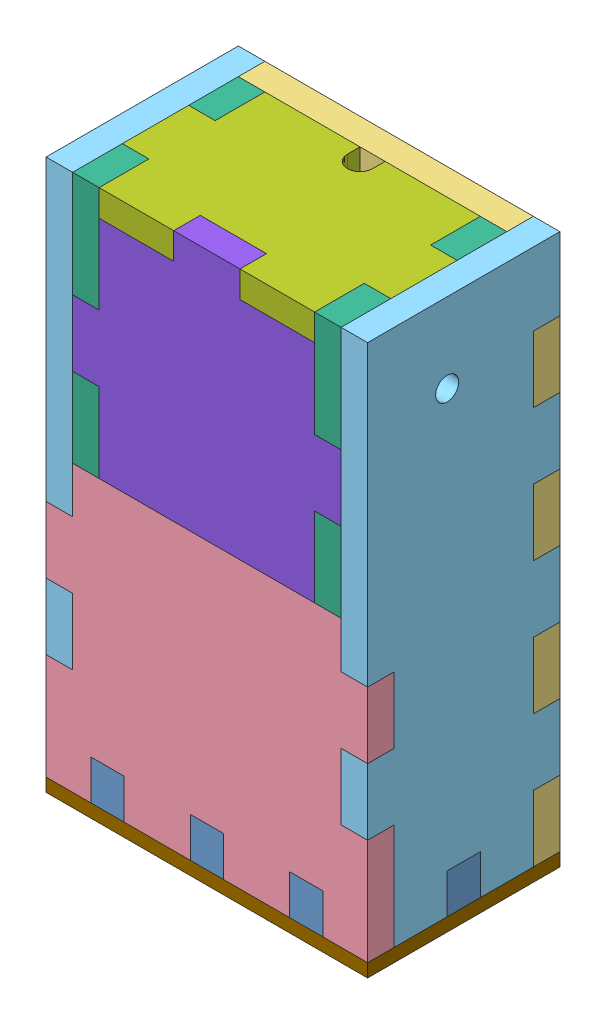
SolidWorks assembly Anduri_karp, configuration Default. Lengths in mm.
Overall size (48.5 83 29).
11 component instances, 9 part files, 30 mates.
Components (placement in the parent):
- andur_esi-1: andur_esi [Default] at (-297.9854 64.2647 100.047) size (48.5 6 29)
- andur_tof-1: andur_tof [Default] at (-282.4854 67.5647 111.047) x (-1 0 0) z (0 0 -1) size (40.2 64.6 13.79)
- andur_alumine-1: andur_alumine [Default] at (-269.9854 146.8647 91.047) x (0 -1 0) z (-1 0 0) size (81 4 48.5)
- andur_pealmine-1: andur_pealmine [Default] at (-310.4854 108.8647 120.047) x (0 -1 0) z (1 0 0) size (43 4 48.5)
- andur_külg-1: andur_külg [Default] at (-269.9854 146.8647 95.047) x (0 -1 0) z (0 0 1) size (81 4 29)
- andur_külg-2: andur_külg [Default] at (-314.4854 146.8647 95.047) x (0 -1 0) z (0 0 1) size (81 4 29)
- andur_kaane_külg-1: andur_kaane_külg [Default] at (-310.4854 146.8647 95.047) x (0 -1 0) z (0 0 1) size (38 4 25)
- andur_kaane_külg-2: andur_kaane_külg [Default] at (-273.9854 146.8647 95.047) x (0 -1 0) z (0 0 1) size (38 4 25)
- andur_kaane_juhtmeauk-1: andur_kaane_juhtmeauk [Default] at (-306.4854 142.8647 95.047) size (40.5 4 25)
- andur_kaane_lagi-1: andur_kaane_lagi [Default] at (-306.4854 108.8647 120.047) x (1 0 0) z (0 1 0) size (40.5 4 38)
- pleksiklaas_2-1: pleksiklaas_2 [Default] at (-314.4854 63.8647 91.047) size (48.5 2 29)
Mates (geometry in assembly coordinates):
- Coincident2: coincident anti-aligned: plane of andur_esi-1 through (-282.4854 71.8647 100.047) normal (0 0 1); plane of andur_tof-1 through (-282.4854 69.1647 100.047) normal (0 0 -1)
- Coincident3: coincident anti-aligned: plane of andur_esi-1 through (-297.9854 71.8647 100.047) normal (0 1 0); plane of andur_tof-1 through (-282.4854 71.8647 111.047) normal (0 -1 0)
- Coincident4: coincident anti-aligned: plane of andur_esi-1 through (-282.4854 71.8647 102.647) normal (-1 0 0); plane of andur_tof-1 through (-282.4854 69.1647 111.047) normal (1 0 0)
- Coincident5: coincident anti-aligned: plane of andur_esi-1 through (-297.9854 71.8647 100.047) normal (0 1 0); plane of andur_alumine-1 through (-269.9854 71.8647 95.047) normal (0 -1 0)
- Coincident6: coincident anti-aligned: plane of andur_esi-1 through (-310.4854 71.8647 95.047) normal (0 0 -1); plane of andur_alumine-1 through (-269.9854 146.8647 95.047) normal (0 0 1)
- Coincident7: coincident aligned: plane of andur_esi-1 through (-269.9854 71.8647 95.047) normal (1 0 0); plane of andur_alumine-1 through (-269.9854 146.8647 95.047) normal (1 0 0)
- Coincident8: coincident aligned: plane of andur_esi-1 through (-307.7354 65.8647 120.047) normal (0 0 1); plane of andur_pealmine-1 through (-310.4854 108.8647 120.047) normal (0 0 1)
- Coincident9: coincident aligned: plane of andur_alumine-1 through (-269.9854 146.8647 95.047) normal (1 0 0); plane of andur_pealmine-1 through (-269.9854 108.8647 116.047) normal (1 0 0)
- Coincident10: coincident anti-aligned: plane of andur_esi-1 through (-297.9854 71.8647 100.047) normal (0 1 0); plane of andur_pealmine-1 through (-310.4854 71.8647 116.047) normal (0 -1 0)
- Coincident11: coincident anti-aligned: plane of andur_esi-1 through (-269.9854 71.8647 95.047) normal (1 0 0); plane of andur_külg-1 through (-269.9854 146.8647 95.047) normal (-1 0 0)
- Coincident12: coincident anti-aligned: plane of andur_esi-1 through (-297.9854 71.8647 100.047) normal (0 1 0); plane of andur_külg-1 through (-265.9854 71.8647 95.047) normal (0 -1 0)
- Coincident13: coincident anti-aligned: plane of andur_pealmine-1 through (-310.4854 108.8647 116.047) normal (0 0 -1); plane of andur_külg-1 through (-265.9854 146.8647 116.047) normal (0 0 1)
- Coincident14: coincident anti-aligned: plane of andur_esi-1 through (-310.4854 71.8647 95.047) normal (-1 0 0); plane of andur_külg-2 through (-310.4854 146.8647 95.047) normal (1 0 0)
- Coincident15: coincident aligned: plane of andur_esi-1 through (-297.9854 65.8647 100.047) normal (0 -1 0); plane of andur_külg-2 through (-314.4854 65.8647 95.047) normal (0 -1 0)
- Coincident16: coincident aligned: plane of andur_alumine-1 through (-269.9854 146.8647 91.047) normal (0 0 -1); plane of andur_külg-2 through (-314.4854 75.8647 91.047) normal (0 0 -1)
- Coincident17: coincident anti-aligned: plane of andur_külg-2 through (-310.4854 146.8647 95.047) normal (1 0 0); plane of andur_kaane_külg-1 through (-310.4854 146.8647 95.047) normal (-1 0 0)
- Coincident18: coincident anti-aligned: plane of andur_alumine-1 through (-269.9854 146.8647 95.047) normal (0 0 1); plane of andur_kaane_külg-1 through (-306.4854 146.8647 95.047) normal (0 0 -1)
- Coincident19: coincident aligned: plane of andur_külg-2 through (-310.4854 146.8647 95.047) normal (0 1 0); plane of andur_kaane_külg-1 through (-306.4854 146.8647 95.047) normal (0 1 0)
- Coincident20: coincident aligned: plane of andur_kaane_külg-1 through (-306.4854 146.8647 120.047) normal (0 0 1); plane of andur_kaane_külg-2 through (-269.9854 146.8647 120.047) normal (0 0 1)
- Coincident21: coincident aligned: plane of andur_kaane_külg-1 through (-306.4854 146.8647 95.047) normal (0 1 0); plane of andur_kaane_külg-2 through (-269.9854 146.8647 95.047) normal (0 1 0)
- Coincident22: coincident anti-aligned: plane of andur_külg-1 through (-269.9854 146.8647 95.047) normal (-1 0 0); plane of andur_kaane_külg-2 through (-269.9854 146.8647 95.047) normal (1 0 0)
- Coincident23: coincident aligned: plane of andur_kaane_külg-1 through (-306.4854 146.8647 95.047) normal (0 1 0); plane of andur_kaane_juhtmeauk-1 through (-306.4854 146.8647 95.047) normal (0 1 0)
- Coincident24: coincident aligned: plane of andur_kaane_külg-1 through (-306.4854 146.8647 120.047) normal (0 0 1); plane of andur_kaane_juhtmeauk-1 through (-306.4854 146.8647 120.047) normal (0 0 1)
- Coincident25: coincident anti-aligned: plane of andur_kaane_külg-2 through (-273.9854 146.8647 95.047) normal (-1 0 0); plane of andur_kaane_juhtmeauk-1 through (-273.9854 146.8647 95.047) normal (1 0 0)
- Coincident26: coincident aligned: plane of andur_kaane_külg-1 through (-306.4854 108.8647 95.047) normal (0 -1 0); plane of andur_kaane_lagi-1 through (-306.4854 108.8647 116.047) normal (0 -1 0)
- Coincident27: coincident aligned: plane of andur_kaane_külg-1 through (-306.4854 146.8647 120.047) normal (0 0 1); plane of andur_kaane_lagi-1 through (-306.4854 108.8647 120.047) normal (0 0 1)
- Coincident28: coincident anti-aligned: plane of andur_kaane_külg-1 through (-306.4854 146.8647 95.047) normal (1 0 0); plane of andur_kaane_lagi-1 through (-306.4854 108.8647 116.047) normal (-1 0 0)
- Coincident29: coincident: plane of andur_esi-1 through (-297.9854 65.8647 100.047) normal (0 -1 0); plane of pleksiklaas_2-1 through (-314.4854 65.8647 91.047) normal (0 1 0)
- Coincident30: coincident: plane of andur_pealmine-1 through (-310.4854 108.8647 120.047) normal (0 0 1); plane of pleksiklaas_2-1 through (-314.4854 65.8647 120.047) normal (0 0 1)
- Coincident31: coincident aligned: plane of andur_külg-2 through (-314.4854 146.8647 95.047) normal (-1 0 0); plane of pleksiklaas_2-1 through (-314.4854 65.8647 91.047) normal (-1 0 0)
